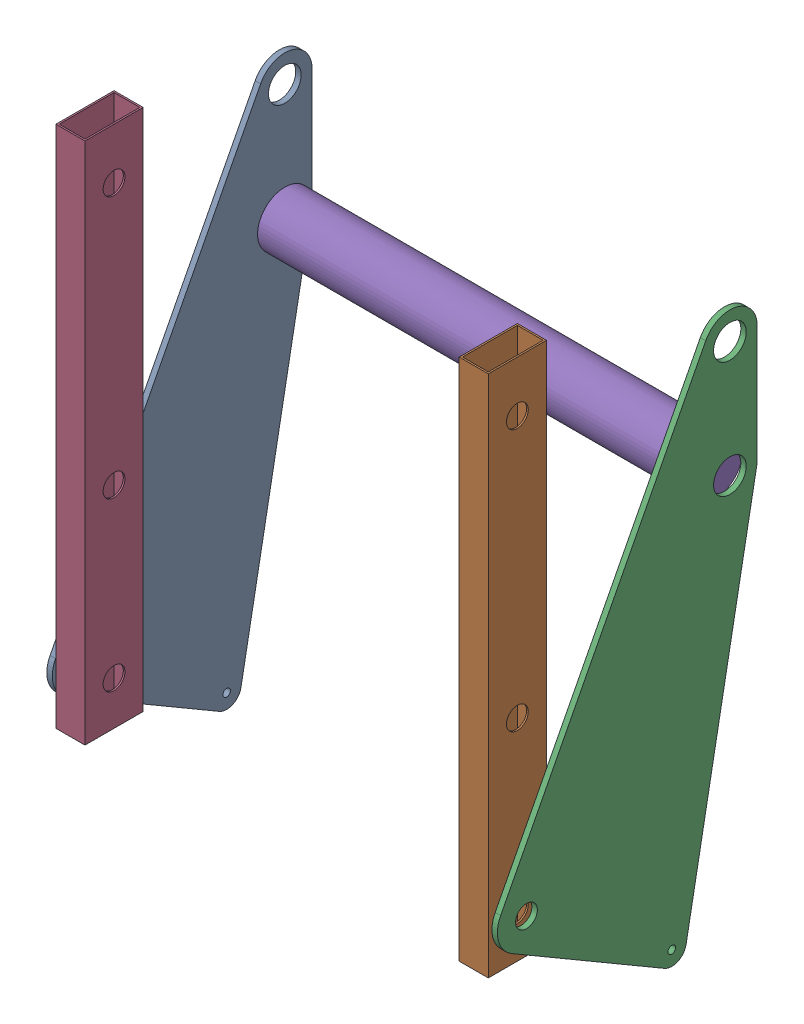
SolidWorks assembly intake_3, configuration Default. Lengths in mm.
Overall size (393.82 520.7 236.69).
5 component instances, 3 part files, 0 mates.
Components (placement in the parent):
- intake_side_rev3SLDPRT-1: intake_side_rev3SLDPRT [Default] at (-293.803 45.2132 287.1603) size (4.76 471.49 227.01)
- end_link_Default_As Machined_-1: end_link_Default_As Machined_ [Default] at (79.2595 108.7132 261.7603) size (25.4 457.2 50.8)
- intake_side_rev3SLDPRT-2: intake_side_rev3SLDPRT [Default] at (95.1345 45.2132 287.1603) size (4.76 471.49 227.01)
- end_link_Default_As Machined_-2: end_link_Default_As Machined_ [Default] at (-273.1655 108.7132 261.7603) size (25.4 457.2 50.8)
- intake_roller-1: intake_roller [Default] at (-293.9207 391.2882 83.9603) x (1 0 0) z (0 0.77759 0.628772) size (381 47.62 47.62)
